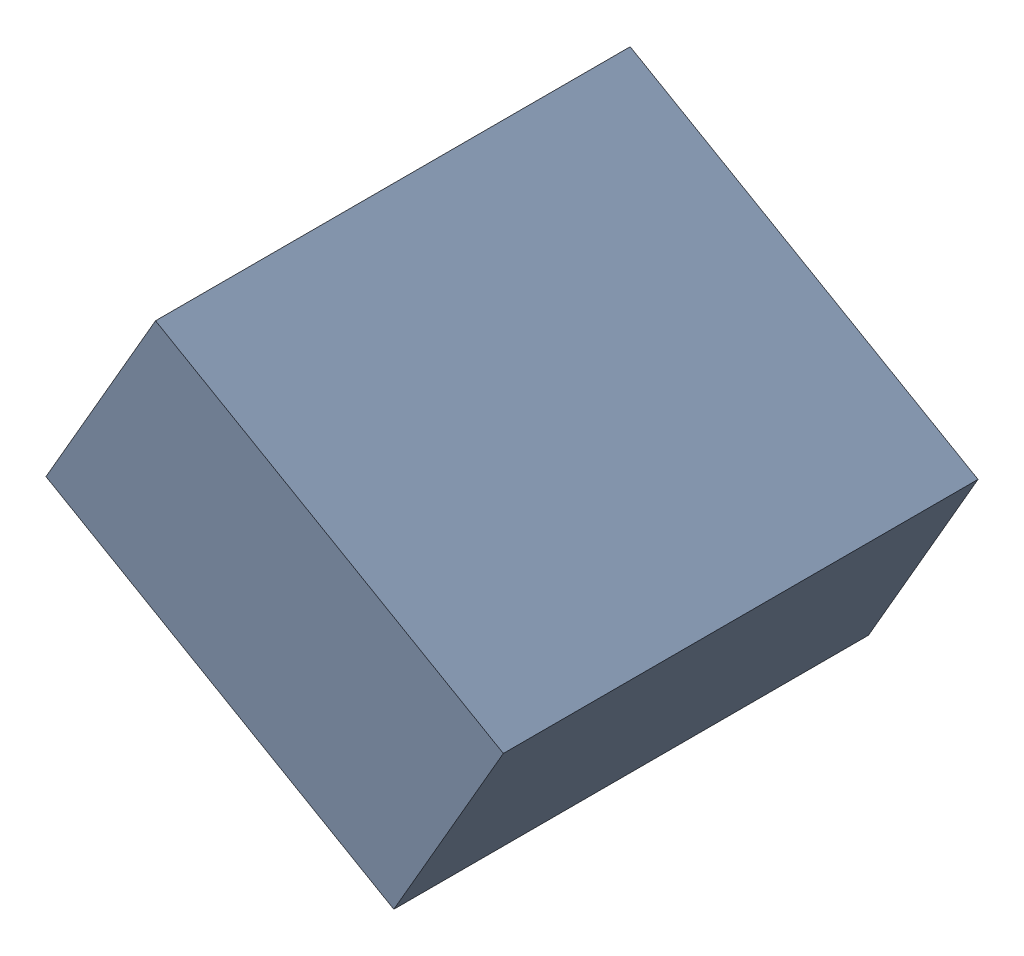
SolidWorks assembly C31_TDA3, configuration Standard. Lengths in mm.
Overall size (1.25 1.07 1.3).
2 component instances, 1 part files, 0 mates.
Components (placement in the parent):
- 885543056-1: 885543056 [Standard] at (51.6512 -31.6689 0) size (1.25 1.07 1.3)
  - Extruded_23-1: Extruded_23 [Standard] at origin size (1.25 1.07 1.3)
